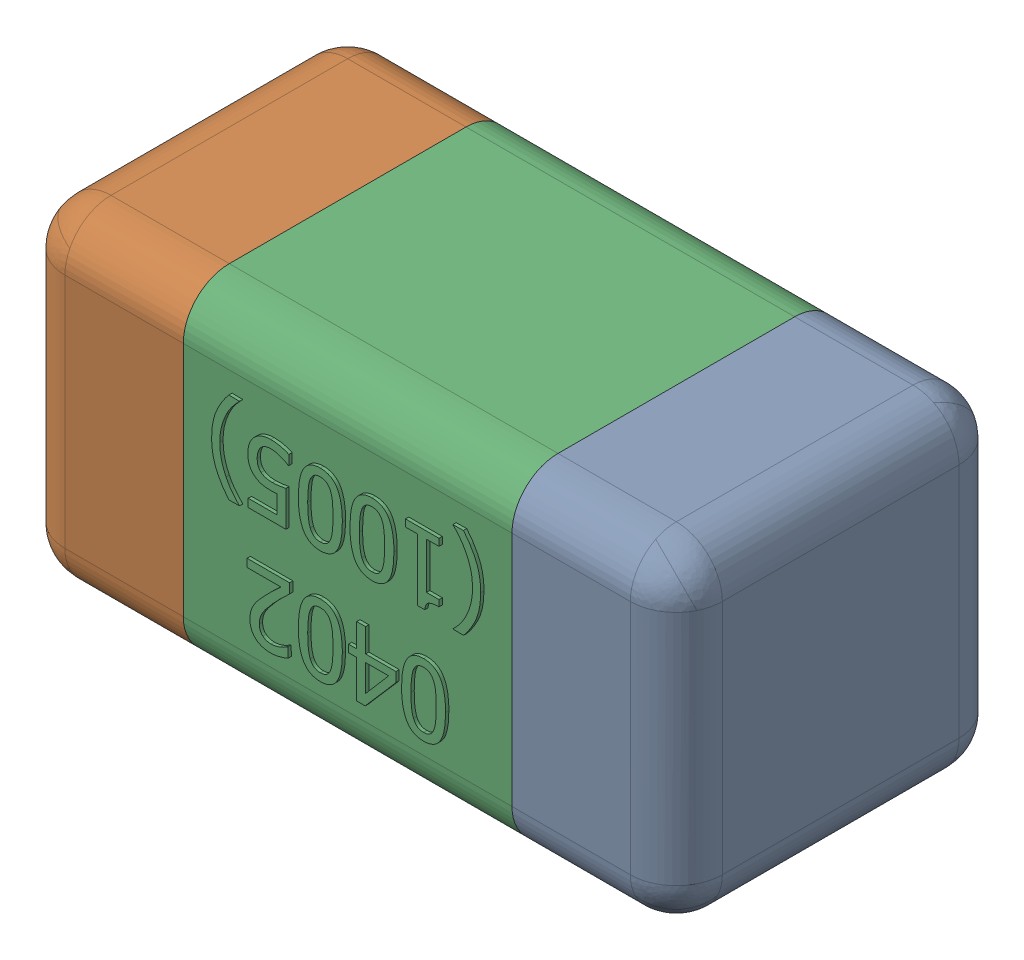
SolidWorks assembly C12, configuration Standard. Lengths in mm.
Overall size (1.01 0.51 0.51).
4 component instances, 3 part files, 0 mates.
Components (placement in the parent):
- C12-subassembly-1-1: C12-subassembly-1 [Standard] at (6.2999 -21 0) x (-1 0 0) z (0 0 1) size (1.01 0.51 0.51)
  - User Library-0402_Cap-1: User Library-0402_Cap [Standard] at origin size (0.26 0.51 0.51)
  - User Library-0402_Cap-1-1: User Library-0402_Cap-1 [Standard] at origin size (0.26 0.5 0.51)
  - User Library-0402_Cap-2-1: User Library-0402_Cap-2 [Standard] at origin size (0.5 0.5 0.51)
